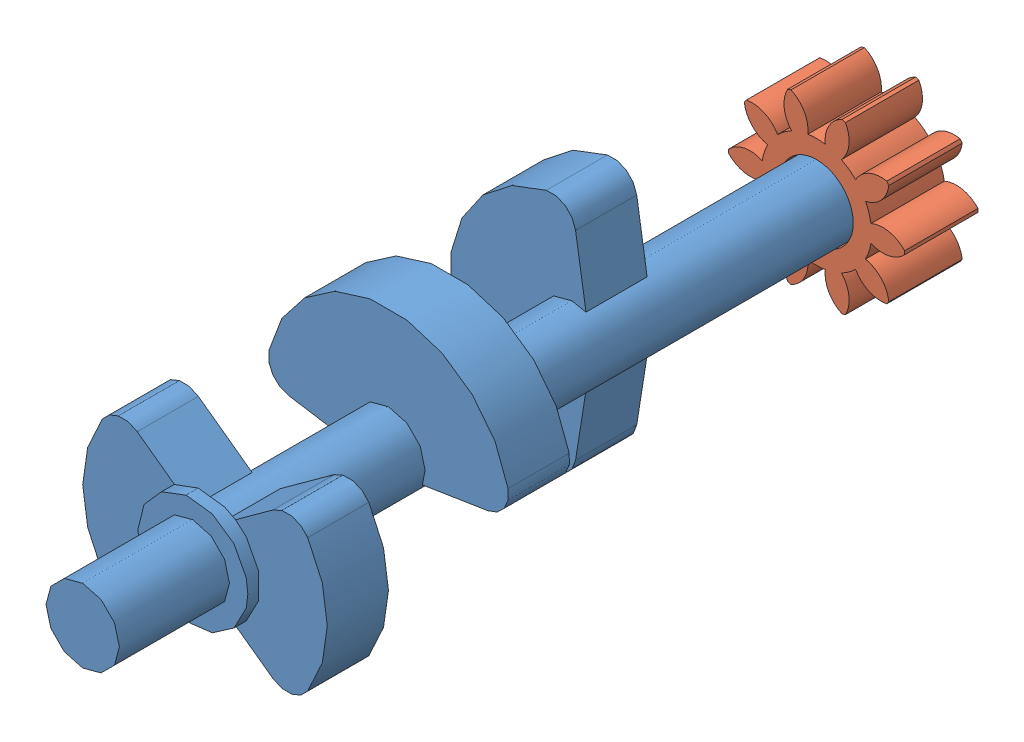
SolidWorks assembly rotor, configuration По умолчанию. Lengths in mm.
Overall size (9 8.9 33.5).
2 component instances, 2 part files, 2 mates.
Components (placement in the parent):
- rotor-1: rotor [По умолчанию] at origin size (9 8.9 33.5)
- spur gear_am-1: spur gear_am [Metric - Spur gear 0.6M 10T 20PA 3FW ---S10N75H50L3N] at (0 0 3) x (0 0 -1) z (1 0 0) size (3 6.89 7.2)
Mates (geometry in assembly coordinates):
- Концентричный1: concentric anti-aligned: cylinder of rotor-1 through (0 0 33.5) axis (0 0 -1) radius 1.5; cylinder of spur gear_am-1 through (0 0 -47.0001) axis (0 0 1) radius 1.5
- Совпадение1: coincident aligned: plane of rotor-1 through (0 0 0) normal (0 0 -1); plane of spur gear_am-1 through (0 0 0) normal (0 0 -1)
